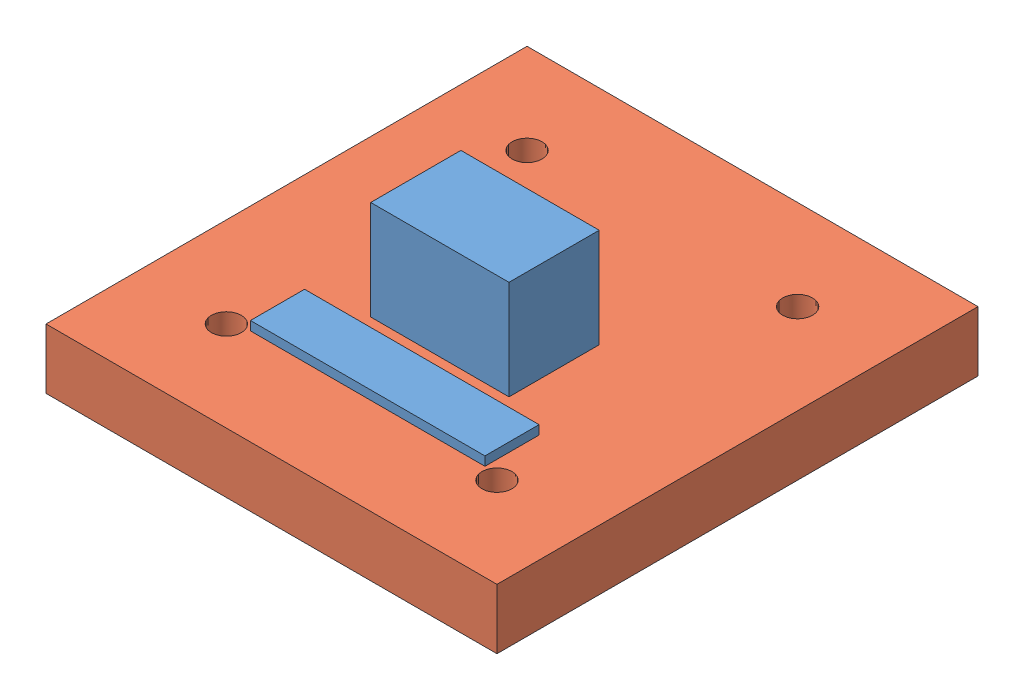
SolidWorks assembly Motor Controller Jig, configuration Default. Lengths in mm.
Overall size (75 26.5 80).
2 component instances, 2 part files, 7 mates.
Components (placement in the parent):
- Motor_Contoller-1: Motor_Contoller [Default] at origin size (55 26.5 60)
- Motor Controller Jig-1: Motor Controller Jig [Default] x (1 0 0) z (0 1 0) size (75 80 10)
Mates (geometry in assembly coordinates):
- Coincident1: coincident aligned: plane of Motor_Contoller-1 through (0 0 0) normal (0 0 1)
- Coincident2: coincident aligned: plane of Motor_Contoller-1 through (0 0 0) normal (0 1 0)
- Coincident3: coincident aligned: plane of Motor_Contoller-1 through (0 0 0) normal (1 0 0)
- InPlace1: in place: plane of Motor Controller Jig-1 through (0 0 0) normal (0 1 0); moOrthogonalPlaneRef_w of Motor Controller Jig-1 through (0 0 0) normal (0 0 -1); plane of Motor Controller Jig-1 through (0 0 0) normal (1 0 0); unknown of Motor Controller Jig-1
- Coincident4: coincident aligned: 
- Coincident5: coincident aligned: plane of Motor Controller Jig-1 through (0 0 0) normal (0 0 -1)
- Coincident6: coincident anti-aligned: plane of Motor Controller Jig-1 through (0 0 0) normal (1 0 0)
